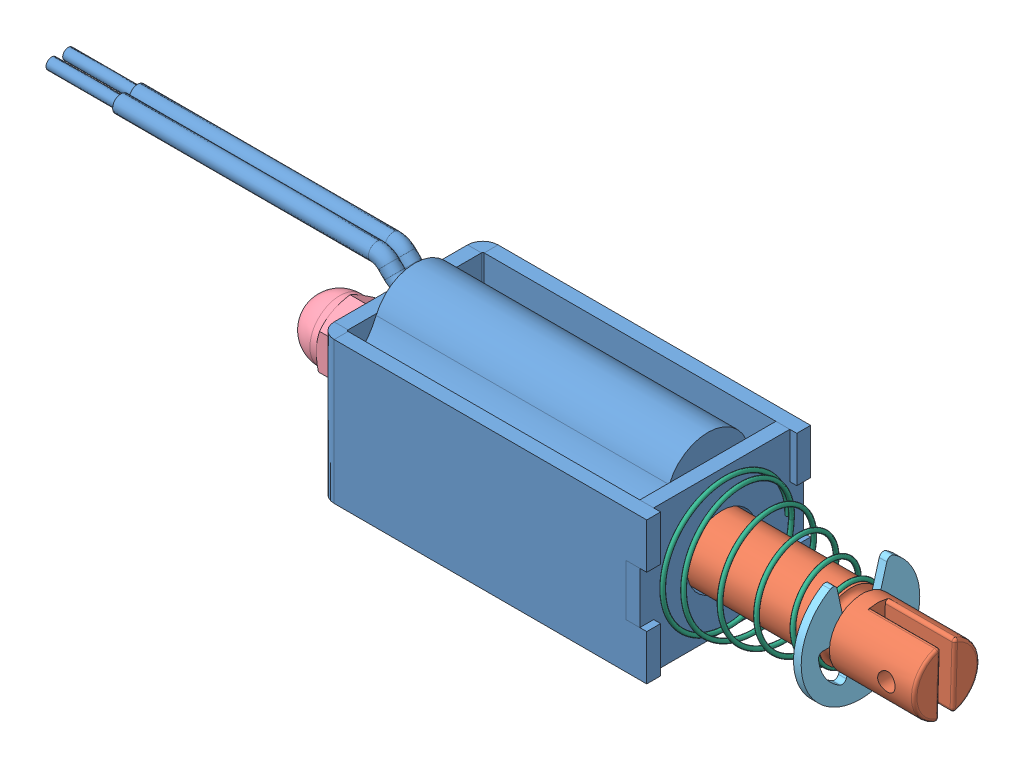
SolidWorks assembly JF-0530B, configuration Défaut. Lengths in mm.
Overall size (81.17 15.98 15).
6 component instances, 6 part files, 15 mates.
Components (placement in the parent):
- Coil-1: Coil [Défaut] at origin size (61.21 15.98 15)
- Plunger-1: Plunger [Défaut] at (34.9665 0 0) x (1 0 0) z (0 -0.031722 -0.999497) size (57.37 6 6)
- O-Ring-1: O-Ring [Défaut] at (-16.3694 0 0) x (0 -0.055151 -0.998478) z (0 0.998478 -0.055151) size (6 1.91 6)
- M3x0,5 Cap Nut-1: M3x0,5 Cap Nut [95514A101] at (-17.3219 0 0) x (0 0.031722 0.999497) z (1 0 0) size (5.5 6.35 6)
- Circlip-1: Circlip [98543A113] at (26.7115 0 0) x (1 0 0) z (0 0.999497 -0.031722) size (0.7 10.85 10.07)
- Spring-1: Spring [1692K49] at (14.365 0 0) x (0 0 -1) z (0 -1 0) size (12.05 12 12)
Mates (geometry in assembly coordinates):
- Coïncidente1: coincident: axis of Coil-1 through (13.095 0 0) axis (-1 0 0); plane of Plunger-1 through (34.9665 0 0) normal (0 -0.031722 -0.999497)
- Coïncidente2: coincident: axis of Coil-1 through (13.095 0 0) axis (-1 0 0); plane of Plunger-1 through (34.9665 0 0) normal (0 -0.999497 0.031722)
- Coïncidente3: coincident: axis of Plunger-1 through (-0.1485 0 0) axis (-1 0 0); axis of O-Ring-1 through (-18.1087 0 0) axis (1 0 0)
- Coaxiale1: concentric: cylinder of Plunger-1 through (-28.4666 0 0) axis (-1 0 0) radius 1.4605; cylinder of M3x0,5 Cap Nut-1 through (-21.1219 0 0) axis (1 0 0) radius 1.5
- Parallèle1: parallel: plane of Plunger-1 through (28.6165 3.0186 0.5395) normal (0 -0.031722 -0.999497); plane of M3x0,5 Cap Nut-1 through (-19.9886 -1.6742 -2.6983) normal (0 -0.031722 -0.999497)
- Tangent1: tangent: torus of O-Ring-1; plane of M3x0,5 Cap Nut-1 through (-17.3219 -3.1738 0.1007) normal (1 0 0)
- Coïncidente5: coincident: axis of Plunger-1 through (25.0027 0 0) axis (1 0 0); axis of Circlip-1 through (27.0615 0 0) axis (-1 0 0)
- Coïncidente6: coincident: plane of Plunger-1 through (34.9665 0 0) normal (0 -0.031722 -0.999497); plane of Circlip-1 through (26.7115 0 0) normal (0 -0.031722 -0.999497)
- Distance2: distance = 8.255 mm: plane of Circlip-1; plane of Plunger-1
- DistanceLimite1: limit distance = 49.9665 mm: plane of Coil-1 through (-15 -6.5 7.5) normal (-1 0 0); plane of Plunger-1 through (34.9665 0 0) normal (1 0 0)
- Coïncidente8: coincident: plane of Plunger-1 through (-17.3219 -1.4992 0.0476) normal (-1 0 0); plane of M3x0,5 Cap Nut-1 through (-17.3219 -3.1738 0.1007) normal (1 0 0)
- Coïncidente9: coincident: plane of Coil-1 through (14.365 0 0) normal (1 0 0); plane of Spring-1
- Coïncidente10: coincident: plane of Spring-1; plane of assembly through (0 0 0) normal (0 0 1)
- Coïncidente11: coincident: plane of Spring-1 through (14.365 0 0) normal (0 -1 0); plane of assembly through (0 0 0) normal (0 1 0)
- DistanceLimite2: limit distance = 11.9965 mm: plane of Circlip-1 through (26.3615 0 0) normal (-1 0 0); plane of Coil-1 through (14.365 0 0) normal (1 0 0)
